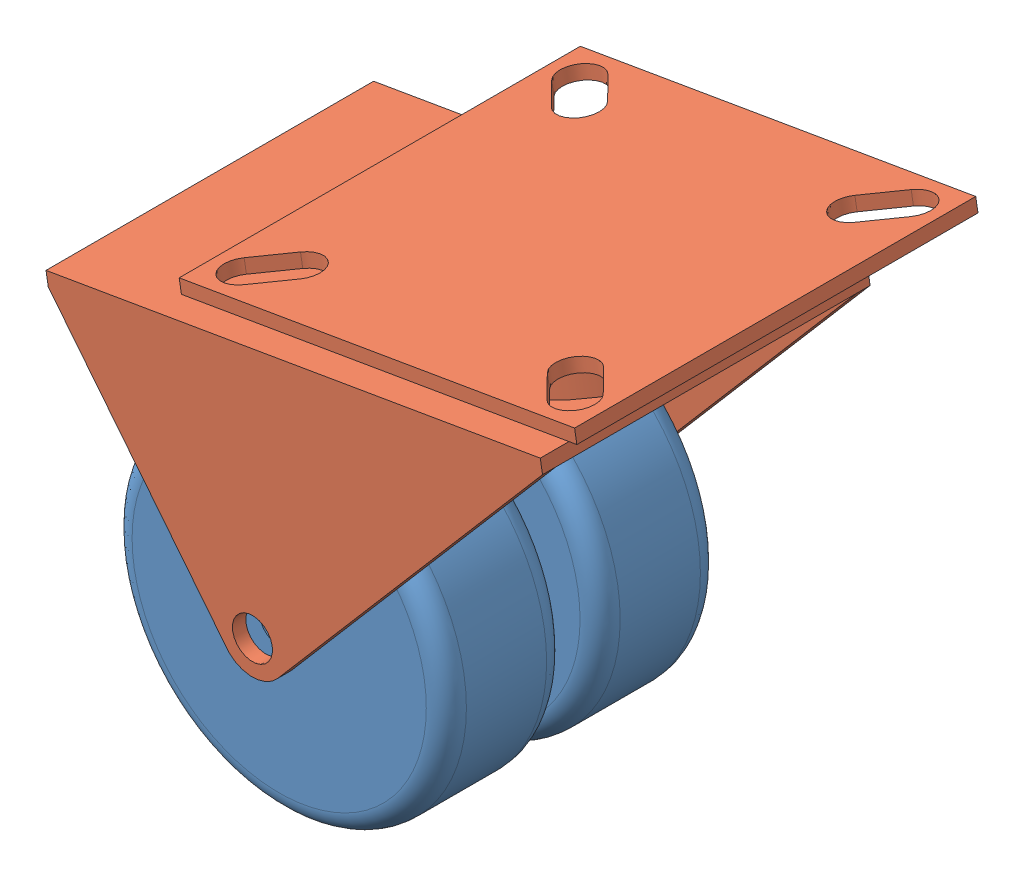
SolidWorks assembly Caster wheel, configuration Default. Lengths in mm.
Overall size (95.01 85.72 60).
3 component instances, 2 part files, 6 mates.
Components (placement in the parent):
- Wheel-1: Wheel [Default] at origin size (50 50 18)
- Wheel-2: Wheel [Default] at (0 0 23) x (0.985694 0.168545 0) z (0 0 1) size (50 50 18)
- Part7-1: Part7 [Default] at (0 0 41) x (0.985694 0.168545 0) z (0 0 1) size (87.5 52 60)
Mates (geometry in assembly coordinates):
- Concentric1: concentric: cylinder of Wheel-1 through (0 0 18) axis (0 0 -1) radius 3; cylinder of Wheel-2 through (0 0 41) axis (0 0 -1) radius 3
- Distance2: distance = 5 mm: plane of Wheel-2 through (0 0 23) normal (0 0 -1); plane of Wheel-1 through (0 0 18) normal (0 0 1)
- InPlace1: in place: plane of Wheel-2 through (0 0 41) normal (0 0 1); plane of ? through (0 0 41) normal (0 0 1); moOrthogonalPlaneRef_w of Wheel-2 through (0 0 41) normal (0 0 1); plane of ? through (0 0 41) normal (0 1 0); plane of Wheel-2 through (0 0 41) normal (0 0 1); plane of ? through (0 0 41) normal (1 0 0); plane of Wheel-2 through (0 0 41) normal (0 0 1); unknown of Part7-1
- Coincident2: coincident: plane of Wheel-2; plane of Part7-1
- Coincident3: coincident: moOrthogonalPlaneRef_w of Wheel-2 through (0 0 41) normal (-0.168545 0.985694 0); plane of Part7-1 through (0 0 41) normal (-0.168545 0.985694 0)
- Coincident4: coincident: moOrthogonalPlaneRef_w of Wheel-2 through (0 0 41) normal (-0.985694 -0.168545 0); plane of Part7-1 through (0 0 41) normal (0.985694 0.168545 0)
